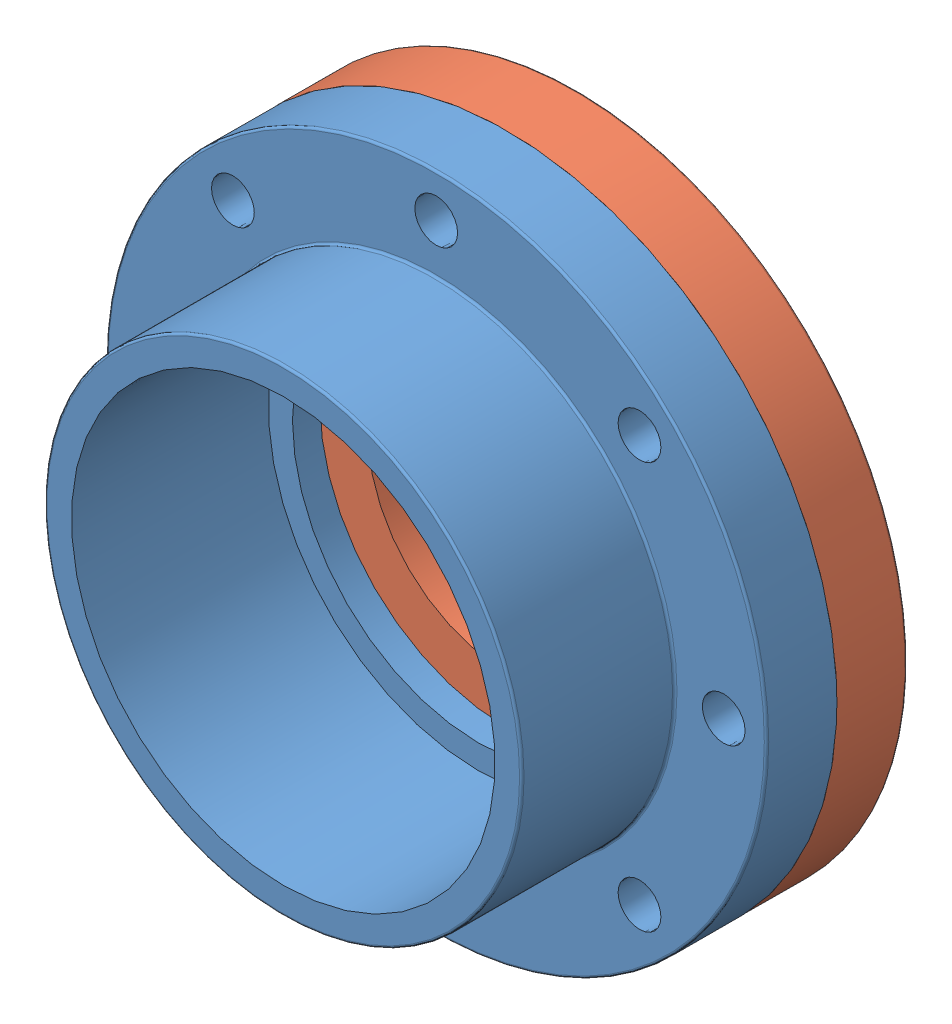
SolidWorks assembly 7inEZTops_Dome_Assembly_1, configuration Default. Lengths in mm.
Overall size (476.84 476.84 223.04).
3 component instances, 3 part files, 4 mates.
Components (placement in the parent):
- 8in PVC Flange-1: 8in PVC Flange [4881K224] at (-97.1505 -37.1415 76.3422) size (342.9 342.9 115.89)
- 7inEZTops_8in PVC Flange Closed - Dome Mount Cut-1: 7inEZTops_8in PVC Flange Closed - Dome Mount Cut [4881K973] at (-97.1505 -37.1415 76.3422) x (0.56667 0.823945 0) z (0 0 -1) size (342.9 342.9 36.51)
- 7inEZTops_Custom Dome_v2-1: 7inEZTops_Custom Dome_v2 [Default] at (-97.1505 -37.1415 58.0859) x (-0.849272 0.527956 0) z (-0.527956 -0.849272 0) size (203.2 88.9 203.2)
Mates (geometry in assembly coordinates):
- Concentric2: concentric anti-aligned: circle of 8in PVC Flange-1; circle of 7inEZTops_8in PVC Flange Closed - Dome Mount Cut-1
- Coincident3: coincident anti-aligned: plane of 8in PVC Flange-1 through (-97.1505 -37.1415 76.3422) normal (0 0 -1); plane of 7inEZTops_8in PVC Flange Closed - Dome Mount Cut-1 through (-97.1505 -37.1415 76.3422) normal (0 0 1)
- Concentric3: concentric aligned: circle of 7inEZTops_8in PVC Flange Closed - Dome Mount Cut-1; circle of 7inEZTops_Custom Dome_v2-1
- Coincident4: coincident anti-aligned: plane of 7inEZTops_8in PVC Flange Closed - Dome Mount Cut-1 through (-7.0546 -99.1051 58.0859) normal (0 0 -1); plane of 7inEZTops_Custom Dome_v2-1 through (-10.8645 -90.7818 58.0859) normal (0 0 1)
